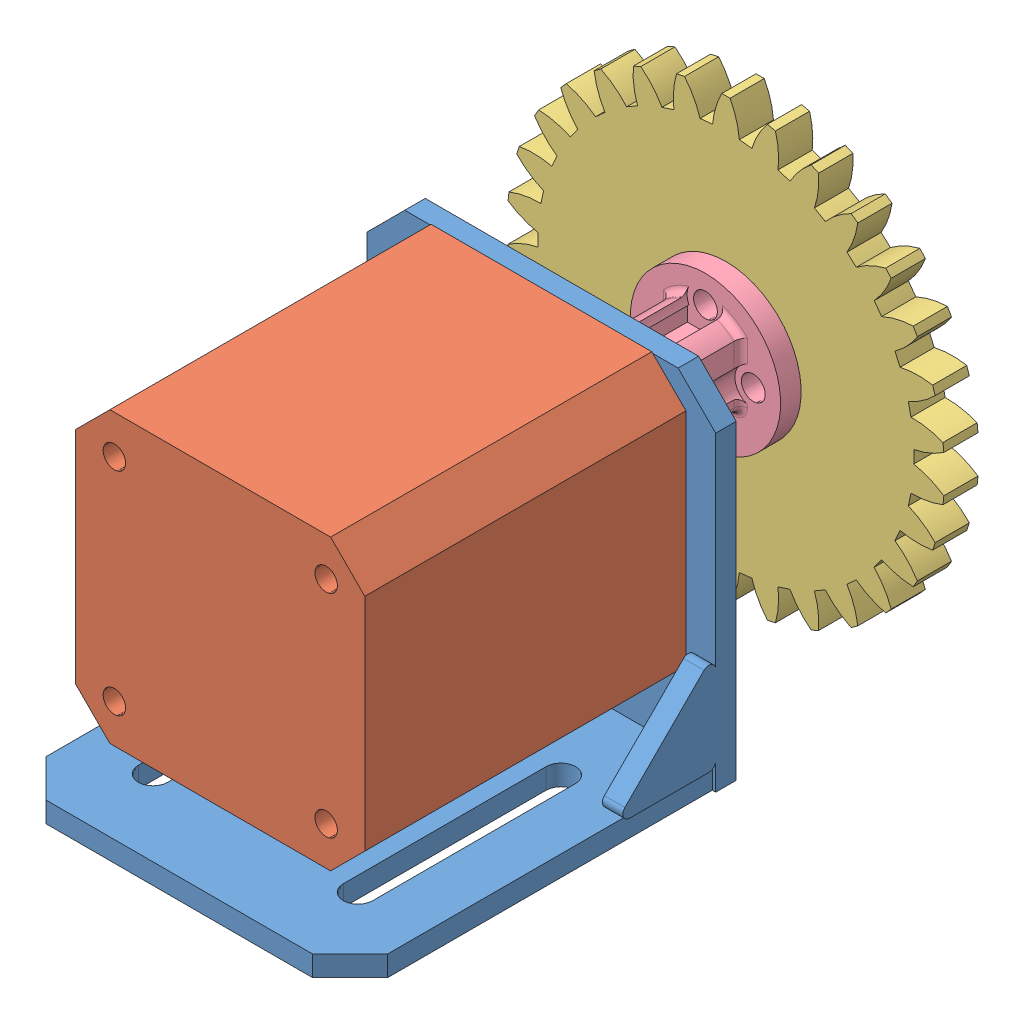
SolidWorks assembly 装配体3, configuration 默认. Lengths in mm.
Overall size (63.76 64 85).
4 component instances, 4 part files, 9 mates.
Components (placement in the parent):
- 电机支架-1: 电机支架 [默认] at (-3.4864 -17.0415 31) size (51 51 56)
- 电机驱动器-1: 电机驱动器 [默认] at (-3.4864 9.9585 31) size (42.3 42.3 71)
- 齿轮2-1: 齿轮2 [默认] at (-3.4864 9.9585 -1) x (0 -1 0) z (0 0 1) size (64 63.76 5)
- 连轴器-1: 连轴器 [默认] at (-3.4864 9.9585 4) x (0 -1 0) z (0 0 1) size (22 22 19)
Mates (geometry in assembly coordinates):
- 同心1: concentric aligned: cylinder of 电机支架-1 through (-3.4864 9.9585 28) axis (0 0 1) radius 11; cylinder of 电机驱动器-1 through (-3.4864 9.9585 29) axis (0 0 1) radius 11
- 同心2: concentric anti-aligned: cylinder of 电机支架-1 through (-18.9864 25.4585 28) axis (0 0 1) radius 1.65; cylinder of 电机驱动器-1 through (-18.9864 25.4585 78) axis (0 0 -1) radius 1.65
- 重合1: coincident anti-aligned: plane of 电机支架-1 through (-3.4864 -17.0415 31) normal (0 0 1); plane of 电机驱动器-1 through (-3.4864 9.9585 31) normal (0 0 -1)
- 同心3: concentric anti-aligned: cylinder of 齿轮2-1 through (-3.4864 2.9585 -99.7692) axis (0 0 1) radius 1.75; cylinder of 连轴器-1 through (-3.4864 2.9585 -86.7692) axis (0 0 -1) radius 1.75
- 重合3: coincident anti-aligned: plane of 齿轮2-1 through (1.5101 23.1386 -89.7692) normal (0 0 1); plane of 连轴器-1 through (-3.4864 9.9585 -89.7692) normal (0 0 -1)
- 同心4: concentric anti-aligned: cylinder of 齿轮2-1 through (-3.4864 16.9585 -99.7692) axis (0 0 1) radius 1.75; cylinder of 连轴器-1 through (-3.4864 16.9585 -86.7692) axis (0 0 -1) radius 1.75
- 重合4: coincident anti-aligned: plane of 电机驱动器-1 through (-1.9864 11.9585 7) normal (0 1 0); plane of 连轴器-1 through (-1.7479 11.9585 -70.7692) normal (0 -1 0)
- 同心5: concentric anti-aligned: cylinder of 电机驱动器-1 through (-3.4864 9.9585 7) axis (0 0 1) radius 2.5; cylinder of 连轴器-1 through (-3.4864 9.9585 -70.7692) axis (0 0 -1) radius 2.65
- 重合5: coincident anti-aligned: plane of 电机驱动器-1 through (-3.4864 9.9585 7) normal (0 0 -1); plane of 连轴器-1 through (-3.4864 9.9585 7) normal (0 0 1)
